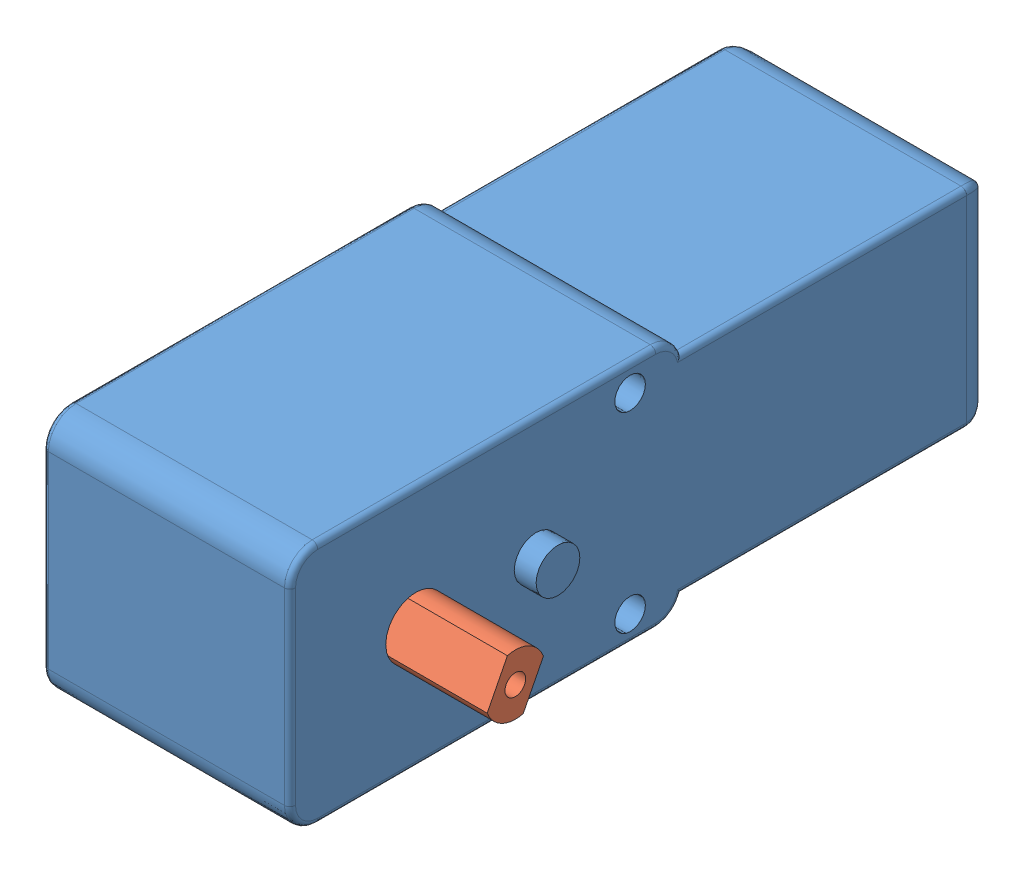
SolidWorks assembly Assem4, configuration Default. Lengths in mm.
Overall size (31.7 22.3 64.4).
2 component instances, 2 part files, 5 mates.
Components (placement in the parent):
- motor-1: motor [Default] at (-22.6 -22.3 0) size (24.6 22.3 64.4)
- motor shaft-1: motor shaft [Default] at (-1.27 -11.15 -11.508) x (0 -0.890994 0.454014) z (1 0 0) size (5.5 3.7 10.37)
Mates (geometry in assembly coordinates):
- Concentric1: concentric anti-aligned: cylinder of motor-1 through (-10.3289 -11.15 -11.508) axis (1 0 0) radius 2.75; cylinder of motor shaft-1 through (0.0411 -11.15 -11.508) axis (-1 0 0) radius 2.75
- Coincident1: coincident anti-aligned: plane of motor-1 through (-10.3289 -11.15 -11.508) normal (1 0 0); plane of motor shaft-1 through (-10.3289 -11.15 -11.508) normal (-1 0 0)
- Coincident2: coincident aligned: plane of motor-1 through (0 -22.3 0) normal (0 0 1); plane of assembly
- Coincident3: coincident aligned: plane of motor-1 through (0 0 0) normal (0 1 0); plane of assembly
- Coincident4: coincident aligned: plane of motor-1 through (0 -22.3 0) normal (1 0 0); plane of assembly
